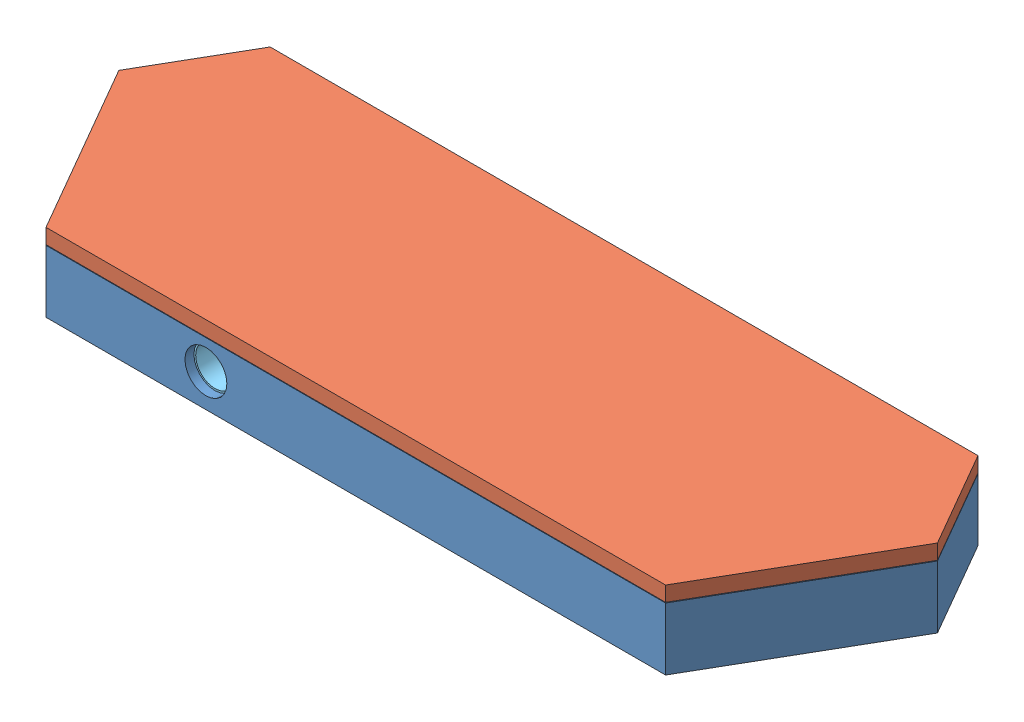
SolidWorks assembly nanoleaf_controller, configuration Défaut. Lengths in mm.
Overall size (149.44 13 140.61).
6 component instances, 6 part files, 16 mates.
Components (placement in the parent):
- nanoleaf_controller_bottom-1: nanoleaf_controller_bottom [Défaut] x (0.5 0 -0.866025) z (0.866025 0 0.5) size (94.1 12 118.23)
- nanoleaf_controller_top-1: nanoleaf_controller_top [Défaut] at (0 13 0) x (1 0 0) z (0 -1 0) size (136.52 44.74 4.8)
- ESP32_Mini_full-1: ESP32_Mini_full [Défaut] at (28 5.1 -22.0946) x (0 0 1) z (-1 0 0) size (31.2 3.67 39)
- 610006243021-1: 610006243021 [Défaut] at (0 6.5 -42.7626) x (0 1 0) z (0 0 -1) size (7.62 7.21 3.7)
- 61300625721-1: 61300625721 [Défaut] at (0 6.5 -43.5034) x (0 -1 0) z (0 0 -1) size (8.22 5.33 8.1) (hidden)
- 694106301002-1: 694106301002 [Default] at (-23.85 5.5 -5) x (0 1 0) z (-1 0 0) size (9.5 14.5 14.5)
Mates (geometry in assembly coordinates):
- Coïncidente8: coincident: plane of nanoleaf_controller_bottom-1 through (0 0 0) normal (1 0 0); plane of assembly through (0 0 0) normal (1 0 0)
- Coïncidente9: coincident: plane of nanoleaf_controller_bottom-1 through (0 0 0) normal (0 1 0); plane of assembly through (0 0 0) normal (0 1 0)
- Coïncidente10: coincident: plane of nanoleaf_controller_bottom-1 through (51.6667 0 0) normal (0 0 1); plane of assembly through (0 0 0) normal (0 0 1)
- Coïncidente16: coincident: plane of nanoleaf_controller_bottom-1 through (0 0 0) normal (1 0 0); plane of 610006243021-1 through (0 6.5 -42.7626) normal (1 0 0)
- Coïncidente17: coincident: plane of nanoleaf_controller_bottom-1 through (0 6.5 0) normal (0 1 0); plane of 610006243021-1 through (0 6.5 -42.7626) normal (0 1 0)
- Coïncidente18: coincident: plane of nanoleaf_controller_bottom-1 through (0 0 0) normal (1 0 0); plane of 61300625721-1 through (0 6.5 -43.5034) normal (-1 0 0)
- Coïncidente19: coincident: plane of nanoleaf_controller_bottom-1 through (0 6.5 0) normal (0 1 0); plane of 61300625721-1 through (0 6.5 -43.5034) normal (0 -1 0)
- Coïncidente20: coincident: plane of nanoleaf_controller_top-1 through (0 13 0) normal (1 0 0); plane of assembly through (0 0 0) normal (1 0 0)
- Coïncidente21: coincident: plane of nanoleaf_controller_top-1 through (0 13 0) normal (0 0 1); plane of assembly through (0 0 0) normal (0 0 1)
- Coïncidente22: coincident: plane of nanoleaf_controller_bottom-1 through (0 12 0) normal (0 1 0); plane of nanoleaf_controller_top-1 through (0 12 0) normal (0 -1 0)
- Parallèle3: parallel: plane of nanoleaf_controller_bottom-1 through (-47.1891 1 -27.2446) normal (0 1 0); plane of 694106301002-1 through (-18.5 1 -1.5) normal (0 -1 0)
- Coïncidente24: coincident: plane of nanoleaf_controller_bottom-1 through (0 0 -1.5) normal (0 0 -1); plane of 694106301002-1 through (-23.85 5.5 -1.5) normal (0 0 1)
- Coaxiale3: concentric: cylinder of nanoleaf_controller_bottom-1 through (-25 5.5 -10) axis (0 0 1) radius 3.5; cylinder of 694106301002-1 through (-25 5.5 -14.6) axis (0 0 1) radius 1
- Coïncidente25: coincident: plane of nanoleaf_controller_bottom-1 through (0 5.1 0) normal (0 1 0); plane of ESP32_Mini_full-1 through (14 5.1 -36.1946) normal (0 -1 0)
- Distance1: distance = 0.5 mm: plane of ESP32_Mini_full-1 through (47.5 6.1 -35.6946) normal (1 0 0); plane of nanoleaf_controller_bottom-1 through (48 6.6 -27.2446) normal (-1 0 0)
- Coïncidente26: coincident: plane of nanoleaf_controller_bottom-1 through (23.5 6.6 -6.4946) normal (0 0 -1); plane of ESP32_Mini_full-1 through (45.5 6.1 -6.4946) normal (0 0 1)
